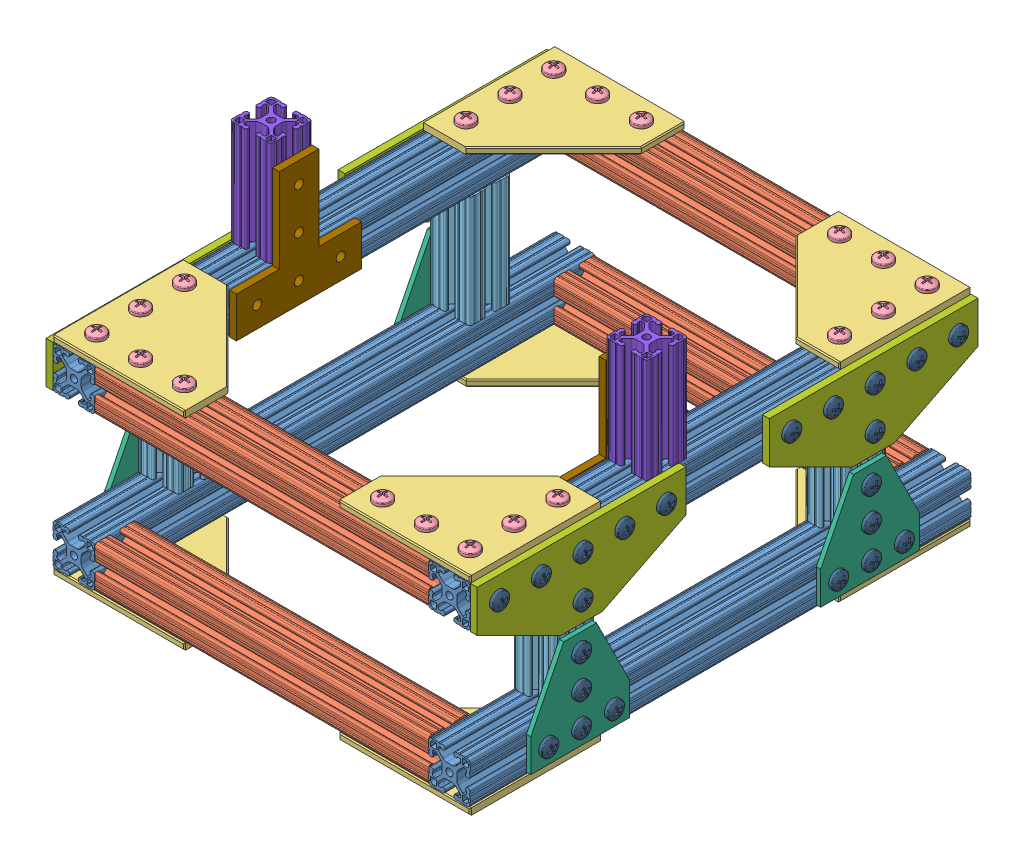
SolidWorks assembly 8020 stand, configuration Default. Lengths in mm.
Overall size (404.67 284.81 457.3).
118 component instances, 10 part files, 45 mates.
Components (placement in the parent):
- 8020 base-1: 8020 base [Default] at (-28.7494 167.9258 15.3611) x (-1 0 0) z (0 0 1) size (381.01 49.83 457.3)
  - 8020 14 inch-1: 8020 14 inch [Default] at (-104.9558 66.744 10.0389) size (38.14 38.25 457.2)
  - 8020 14 inch-2: 8020 14 inch [Default] at (237.9237 66.744 10.0389) size (38.14 38.25 457.2)
  - 8020 8 inch-1: 8020 8 inch [Default] at (34.7301 66.6403 98.9247) x (0 0 -1) z (1 0 0) size (38.14 38.25 304.8)
  - 8020 8 inch-2: 8020 8 inch [Default] at (288.7301 66.744 327.553) x (0 0 1) z (-1 0 0) size (38.14 38.25 304.8)
  - 8020 5 hole plate-1: 8020 5 hole plate [Default] at (29.7356 167.9258 361.7911) x (1 0 0) z (0 -1 0) size (120 120 6)
  - 8020 5 hole plate-2: 8020 5 hole plate [Default] at (293.7245 161.9258 361.7911) x (-1 0 0) z (0 1 0) size (120 120 6)
  - 8020 5 hole plate-3: 8020 5 hole plate [Default] at (293.7245 168.1331 64.6867) x (-1 0 0) z (0 -1 0) size (120 120 6)
  - 8020 5 hole plate-4: 8020 5 hole plate [Default] at (51.2984 167.9258 43.1239) x (0 0 1) z (0 -1 0) size (120 120 6)
  - CR-PHMS 0.3125-18x0.5x0.5-N-1: CR-PHMS 0.3125-18x0.5x0.5-N [CR-PHMS 0.3125-18x0.5x0.5-N] at (332.2095 173.6703 84.6389) x (0 -1 0) z (0 0 1) size (18.18 15.62 15.62)
  - CR-PHMS 0.3125-18x0.5x0.5-N-2: CR-PHMS 0.3125-18x0.5x0.5-N [CR-PHMS 0.3125-18x0.5x0.5-N] at (332.2095 173.6703 44.6389) x (0 -1 0) z (0 0 1) size (18.18 15.62 15.62)
  - CR-PHMS 0.3125-18x0.5x0.5-N-3: CR-PHMS 0.3125-18x0.5x0.5-N [CR-PHMS 0.3125-18x0.5x0.5-N] at (332.2095 173.6703 4.6389) x (0 -1 0) z (0 0 1) size (18.18 15.62 15.62)
  - CR-PHMS 0.3125-18x0.5x0.5-N-4: CR-PHMS 0.3125-18x0.5x0.5-N [CR-PHMS 0.3125-18x0.5x0.5-N] at (292.2095 173.6703 4.6389) x (0 -1 0) z (0 0 1) size (18.18 15.62 15.62)
  - CR-PHMS 0.3125-18x0.5x0.5-N-5: CR-PHMS 0.3125-18x0.5x0.5-N [CR-PHMS 0.3125-18x0.5x0.5-N] at (252.2095 173.6703 4.6389) x (0 -1 0) z (0 0 1) size (18.18 15.62 15.62)
  - CR-PHMS 0.3125-18x0.5x0.5-N-6: CR-PHMS 0.3125-18x0.5x0.5-N [CR-PHMS 0.3125-18x0.5x0.5-N] at (-8.7494 173.463 84.6389) x (0 -1 0) z (0 0 1) size (18.18 15.62 15.62)
  - CR-PHMS 0.3125-18x0.5x0.5-N-7: CR-PHMS 0.3125-18x0.5x0.5-N [CR-PHMS 0.3125-18x0.5x0.5-N] at (-8.7494 173.463 44.6389) x (0 -1 0) z (0 0 1) size (18.18 15.62 15.62)
  - CR-PHMS 0.3125-18x0.5x0.5-N-8: CR-PHMS 0.3125-18x0.5x0.5-N [CR-PHMS 0.3125-18x0.5x0.5-N] at (-8.7494 173.463 4.6389) x (0 -1 0) z (0 0 1) size (18.18 15.62 15.62)
  - CR-PHMS 0.3125-18x0.5x0.5-N-9: CR-PHMS 0.3125-18x0.5x0.5-N [CR-PHMS 0.3125-18x0.5x0.5-N] at (31.2506 173.463 4.6389) x (0 -1 0) z (0 0 1) size (18.18 15.62 15.62)
  - CR-PHMS 0.3125-18x0.5x0.5-N-10: CR-PHMS 0.3125-18x0.5x0.5-N [CR-PHMS 0.3125-18x0.5x0.5-N] at (71.2506 173.463 4.6389) x (0 -1 0) z (0 0 1) size (18.18 15.62 15.62)
  - CR-PHMS 0.3125-18x0.5x0.5-N-11: CR-PHMS 0.3125-18x0.5x0.5-N [CR-PHMS 0.3125-18x0.5x0.5-N] at (-8.7494 173.463 341.8389) x (0 -1 0) z (0 0 1) size (18.18 15.62 15.62)
  - CR-PHMS 0.3125-18x0.5x0.5-N-12: CR-PHMS 0.3125-18x0.5x0.5-N [CR-PHMS 0.3125-18x0.5x0.5-N] at (-8.7494 173.463 381.8389) x (0 -1 0) z (0 0 1) size (18.18 15.62 15.62)
  - CR-PHMS 0.3125-18x0.5x0.5-N-13: CR-PHMS 0.3125-18x0.5x0.5-N [CR-PHMS 0.3125-18x0.5x0.5-N] at (-8.7494 173.463 421.8389) x (0 -1 0) z (0 0 1) size (18.18 15.62 15.62)
  - CR-PHMS 0.3125-18x0.5x0.5-N-14: CR-PHMS 0.3125-18x0.5x0.5-N [CR-PHMS 0.3125-18x0.5x0.5-N] at (31.2506 173.463 421.8389) x (0 -1 0) z (0 0 1) size (18.18 15.62 15.62)
  - CR-PHMS 0.3125-18x0.5x0.5-N-15: CR-PHMS 0.3125-18x0.5x0.5-N [CR-PHMS 0.3125-18x0.5x0.5-N] at (71.2506 173.463 421.8389) x (0 -1 0) z (0 0 1) size (18.18 15.62 15.62)
  - CR-PHMS 0.3125-18x0.5x0.5-N-16: CR-PHMS 0.3125-18x0.5x0.5-N [CR-PHMS 0.3125-18x0.5x0.5-N] at (332.2095 173.463 421.8389) x (0 -1 0) z (0 0 1) size (18.18 15.62 15.62)
  - CR-PHMS 0.3125-18x0.5x0.5-N-17: CR-PHMS 0.3125-18x0.5x0.5-N [CR-PHMS 0.3125-18x0.5x0.5-N] at (292.2095 173.463 421.8389) x (0 -1 0) z (0 0 1) size (18.18 15.62 15.62)
  - CR-PHMS 0.3125-18x0.5x0.5-N-18: CR-PHMS 0.3125-18x0.5x0.5-N [CR-PHMS 0.3125-18x0.5x0.5-N] at (252.2095 173.463 421.8389) x (0 -1 0) z (0 0 1) size (18.18 15.62 15.62)
  - CR-PHMS 0.3125-18x0.5x0.5-N-19: CR-PHMS 0.3125-18x0.5x0.5-N [CR-PHMS 0.3125-18x0.5x0.5-N] at (332.2095 173.463 381.8389) x (0 -1 0) z (0 0 1) size (18.18 15.62 15.62)
  - CR-PHMS 0.3125-18x0.5x0.5-N-20: CR-PHMS 0.3125-18x0.5x0.5-N [CR-PHMS 0.3125-18x0.5x0.5-N] at (332.2095 173.463 341.8389) x (0 -1 0) z (0 0 1) size (18.18 15.62 15.62)
- 8020 base-2: 8020 base [Default] at (-352.2326 21.7379 15.3611) size (381.01 49.83 457.3)
  - 8020 14 inch-1: 8020 14 inch [Default] at (-104.9558 66.744 10.0389) size (38.14 38.25 457.2)
  - 8020 14 inch-2: 8020 14 inch [Default] at (237.9237 66.744 10.0389) size (38.14 38.25 457.2)
  - 8020 8 inch-1: 8020 8 inch [Default] at (34.7301 66.6403 98.9247) x (0 0 -1) z (1 0 0) size (38.14 38.25 304.8)
  - 8020 8 inch-2: 8020 8 inch [Default] at (288.7301 66.744 327.553) x (0 0 1) z (-1 0 0) size (38.14 38.25 304.8)
  - 8020 5 hole plate-1: 8020 5 hole plate [Default] at (29.7356 167.9258 361.7911) x (1 0 0) z (0 -1 0) size (120 120 6)
  - 8020 5 hole plate-2: 8020 5 hole plate [Default] at (293.7245 161.9258 361.7911) x (-1 0 0) z (0 1 0) size (120 120 6)
  - 8020 5 hole plate-3: 8020 5 hole plate [Default] at (293.7245 168.1331 64.6867) x (-1 0 0) z (0 -1 0) size (120 120 6)
  - 8020 5 hole plate-4: 8020 5 hole plate [Default] at (51.2984 167.9258 43.1239) x (0 0 1) z (0 -1 0) size (120 120 6)
  - CR-PHMS 0.3125-18x0.5x0.5-N-1: CR-PHMS 0.3125-18x0.5x0.5-N [CR-PHMS 0.3125-18x0.5x0.5-N] at (332.2095 173.6703 84.6389) x (0 -1 0) z (0 0 1) size (18.18 15.62 15.62)
  - CR-PHMS 0.3125-18x0.5x0.5-N-2: CR-PHMS 0.3125-18x0.5x0.5-N [CR-PHMS 0.3125-18x0.5x0.5-N] at (332.2095 173.6703 44.6389) x (0 -1 0) z (0 0 1) size (18.18 15.62 15.62)
  - CR-PHMS 0.3125-18x0.5x0.5-N-3: CR-PHMS 0.3125-18x0.5x0.5-N [CR-PHMS 0.3125-18x0.5x0.5-N] at (332.2095 173.6703 4.6389) x (0 -1 0) z (0 0 1) size (18.18 15.62 15.62)
  - CR-PHMS 0.3125-18x0.5x0.5-N-4: CR-PHMS 0.3125-18x0.5x0.5-N [CR-PHMS 0.3125-18x0.5x0.5-N] at (292.2095 173.6703 4.6389) x (0 -1 0) z (0 0 1) size (18.18 15.62 15.62)
  - CR-PHMS 0.3125-18x0.5x0.5-N-5: CR-PHMS 0.3125-18x0.5x0.5-N [CR-PHMS 0.3125-18x0.5x0.5-N] at (252.2095 173.6703 4.6389) x (0 -1 0) z (0 0 1) size (18.18 15.62 15.62)
  - CR-PHMS 0.3125-18x0.5x0.5-N-6: CR-PHMS 0.3125-18x0.5x0.5-N [CR-PHMS 0.3125-18x0.5x0.5-N] at (-8.7494 173.463 84.6389) x (0 -1 0) z (0 0 1) size (18.18 15.62 15.62)
  - CR-PHMS 0.3125-18x0.5x0.5-N-7: CR-PHMS 0.3125-18x0.5x0.5-N [CR-PHMS 0.3125-18x0.5x0.5-N] at (-8.7494 173.463 44.6389) x (0 -1 0) z (0 0 1) size (18.18 15.62 15.62)
  - CR-PHMS 0.3125-18x0.5x0.5-N-8: CR-PHMS 0.3125-18x0.5x0.5-N [CR-PHMS 0.3125-18x0.5x0.5-N] at (-8.7494 173.463 4.6389) x (0 -1 0) z (0 0 1) size (18.18 15.62 15.62)
  - CR-PHMS 0.3125-18x0.5x0.5-N-9: CR-PHMS 0.3125-18x0.5x0.5-N [CR-PHMS 0.3125-18x0.5x0.5-N] at (31.2506 173.463 4.6389) x (0 -1 0) z (0 0 1) size (18.18 15.62 15.62)
  - CR-PHMS 0.3125-18x0.5x0.5-N-10: CR-PHMS 0.3125-18x0.5x0.5-N [CR-PHMS 0.3125-18x0.5x0.5-N] at (71.2506 173.463 4.6389) x (0 -1 0) z (0 0 1) size (18.18 15.62 15.62)
  - CR-PHMS 0.3125-18x0.5x0.5-N-11: CR-PHMS 0.3125-18x0.5x0.5-N [CR-PHMS 0.3125-18x0.5x0.5-N] at (-8.7494 173.463 341.8389) x (0 -1 0) z (0 0 1) size (18.18 15.62 15.62)
  - CR-PHMS 0.3125-18x0.5x0.5-N-12: CR-PHMS 0.3125-18x0.5x0.5-N [CR-PHMS 0.3125-18x0.5x0.5-N] at (-8.7494 173.463 381.8389) x (0 -1 0) z (0 0 1) size (18.18 15.62 15.62)
  - CR-PHMS 0.3125-18x0.5x0.5-N-13: CR-PHMS 0.3125-18x0.5x0.5-N [CR-PHMS 0.3125-18x0.5x0.5-N] at (-8.7494 173.463 421.8389) x (0 -1 0) z (0 0 1) size (18.18 15.62 15.62)
  - CR-PHMS 0.3125-18x0.5x0.5-N-14: CR-PHMS 0.3125-18x0.5x0.5-N [CR-PHMS 0.3125-18x0.5x0.5-N] at (31.2506 173.463 421.8389) x (0 -1 0) z (0 0 1) size (18.18 15.62 15.62)
  - CR-PHMS 0.3125-18x0.5x0.5-N-15: CR-PHMS 0.3125-18x0.5x0.5-N [CR-PHMS 0.3125-18x0.5x0.5-N] at (71.2506 173.463 421.8389) x (0 -1 0) z (0 0 1) size (18.18 15.62 15.62)
  - CR-PHMS 0.3125-18x0.5x0.5-N-16: CR-PHMS 0.3125-18x0.5x0.5-N [CR-PHMS 0.3125-18x0.5x0.5-N] at (332.2095 173.463 421.8389) x (0 -1 0) z (0 0 1) size (18.18 15.62 15.62)
  - CR-PHMS 0.3125-18x0.5x0.5-N-17: CR-PHMS 0.3125-18x0.5x0.5-N [CR-PHMS 0.3125-18x0.5x0.5-N] at (292.2095 173.463 421.8389) x (0 -1 0) z (0 0 1) size (18.18 15.62 15.62)
  - CR-PHMS 0.3125-18x0.5x0.5-N-18: CR-PHMS 0.3125-18x0.5x0.5-N [CR-PHMS 0.3125-18x0.5x0.5-N] at (252.2095 173.463 421.8389) x (0 -1 0) z (0 0 1) size (18.18 15.62 15.62)
  - CR-PHMS 0.3125-18x0.5x0.5-N-19: CR-PHMS 0.3125-18x0.5x0.5-N [CR-PHMS 0.3125-18x0.5x0.5-N] at (332.2095 173.463 381.8389) x (0 -1 0) z (0 0 1) size (18.18 15.62 15.62)
  - CR-PHMS 0.3125-18x0.5x0.5-N-20: CR-PHMS 0.3125-18x0.5x0.5-N [CR-PHMS 0.3125-18x0.5x0.5-N] at (332.2095 173.463 341.8389) x (0 -1 0) z (0 0 1) size (18.18 15.62 15.62)
- 8020 4 inch-4: 8020 4 inch [Default] at (-114.2794 120.2318 285.5457) x (1 0 0) z (0 -1 0) size (38.14 38.25 101.6)
- 8020 T plate-1: 8020 T plate [Default] at (4.0064 1.7166 361.919) x (0 0 1) z (-1 0 0) size (90 90 4)
- 8020 T plate 2-1: 8020 T plate 2 [Default] at (6.3564 183.9362 266.7) x (0 0 -1) z (0 -1 0) size (190.5 6.35 76.2)
- 8020 4 inch-5: 8020 4 inch [Default] at (-114.2794 69.4318 171.6543) x (1 0 0) z (0 1 0) size (38.14 38.25 101.6)
- 8020 T plate 2-2: 8020 T plate 2 [Default] at (6.3564 183.9362 0) x (0 0 -1) z (0 -1 0) size (190.5 6.35 76.2)
- 8020 T plate-5: 8020 T plate [Default] at (0.0064 1.7166 95.281) x (0 0 -1) z (1 0 0) size (90 90 4)
- 8020 T plate 2-3: 8020 T plate 2 [Default] at (-387.3564 183.9362 457.2) x (0 0 1) z (0 -1 0) size (190.5 6.35 76.2)
- 8020 T plate 2-4: 8020 T plate 2 [Default] at (-387.3564 183.9362 190.5) x (0 0 1) z (0 -1 0) size (190.5 6.35 76.2)
- 8020 4 inch-6: 8020 4 inch [Default] at (-266.7206 120.2318 171.6543) x (-1 0 0) z (0 -1 0) size (38.14 38.25 101.6)
- 8020 T plate-6: 8020 T plate [Default] at (-385.0064 1.7166 95.281) x (0 0 -1) z (1 0 0) size (90 90 4)
- 8020 T plate-7: 8020 T plate [Default] at (-381.0064 1.7166 361.919) x (0 0 1) z (-1 0 0) size (90 90 4)
- 8020 4 inch-7: 8020 4 inch [Default] at (-266.7206 69.4318 285.5457) x (-1 0 0) z (0 1 0) size (38.14 38.25 101.6)
- 8020 5 inch-1: 8020 5 inch [Default] at (-114.309 209.271 353.3149) x (1 0 0) z (0 1 0) size (38.14 38.25 95.25)
- 8020 thin t-1: 8020 thin t [Default] at (-38.1026 145.7334 219.8633) x (0 0 1) z (0 1 0) size (114.3 6.35 114.3)
- 8020 5 inch-2: 8020 5 inch [Default] at (-266.691 253.721 353.3149) x (-1 0 0) z (0 -1 0) size (38.14 38.25 95.25)
- 8020 thin t-2: 8020 thin t [Default] at (-342.8974 145.7334 334.1633) x (0 0 -1) z (0 1 0) size (114.3 6.35 114.3)
- CR-PHMS 0.3125-24x0.5x0.5-N-2: CR-PHMS 0.3125-24x0.5x0.5-N [CR-PHMS 0.3125-24x0.5x0.5-N] at (11.8936 164.8862 438.15) x (-1 0 0) z (0 0.924225 0.381849) size (18.18 15.62 15.62)
- CR-PHMS 0.3125-24x0.5x0.5-N-3: CR-PHMS 0.3125-24x0.5x0.5-N [CR-PHMS 0.3125-24x0.5x0.5-N] at (11.8936 164.8862 400.05) x (-1 0 0) z (0 0.924225 0.381849) size (18.18 15.62 15.62)
- CR-PHMS 0.3125-24x0.5x0.5-N-4: CR-PHMS 0.3125-24x0.5x0.5-N [CR-PHMS 0.3125-24x0.5x0.5-N] at (11.8936 164.8862 361.95) x (-1 0 0) z (0 0.924225 0.381849) size (18.18 15.62 15.62)
- CR-PHMS 0.3125-24x0.5x0.5-N-5: CR-PHMS 0.3125-24x0.5x0.5-N [CR-PHMS 0.3125-24x0.5x0.5-N] at (11.8936 164.8862 323.85) x (-1 0 0) z (0 0.924225 0.381849) size (18.18 15.62 15.62)
- CR-PHMS 0.3125-24x0.5x0.5-N-6: CR-PHMS 0.3125-24x0.5x0.5-N [CR-PHMS 0.3125-24x0.5x0.5-N] at (11.8936 164.8862 285.75) x (-1 0 0) z (0 0.924225 0.381849) size (18.18 15.62 15.62)
- CR-PHMS 0.3125-24x0.5x0.5-N-7: CR-PHMS 0.3125-24x0.5x0.5-N [CR-PHMS 0.3125-24x0.5x0.5-N] at (11.8936 126.7862 361.95) x (-1 0 0) z (0 0.924225 0.381849) size (18.18 15.62 15.62)
- CR-PHMS 0.3125-24x0.5x0.5-N-8: CR-PHMS 0.3125-24x0.5x0.5-N [CR-PHMS 0.3125-24x0.5x0.5-N] at (9.5436 84.0323 360.9344) x (-1 0 0) z (0 0.924225 0.381849) size (18.18 15.62 15.62)
- CR-PHMS 0.3125-24x0.5x0.5-N-9: CR-PHMS 0.3125-24x0.5x0.5-N [CR-PHMS 0.3125-24x0.5x0.5-N] at (9.5436 54.0323 360.9344) x (-1 0 0) z (0 0.924225 0.381849) size (18.18 15.62 15.62)
- CR-PHMS 0.3125-24x0.5x0.5-N-10: CR-PHMS 0.3125-24x0.5x0.5-N [CR-PHMS 0.3125-24x0.5x0.5-N] at (9.5436 24.0323 330.9344) x (-1 0 0) z (0 0.924225 0.381849) size (18.18 15.62 15.62)
- CR-PHMS 0.3125-24x0.5x0.5-N-11: CR-PHMS 0.3125-24x0.5x0.5-N [CR-PHMS 0.3125-24x0.5x0.5-N] at (9.5436 24.0323 360.9344) x (-1 0 0) z (0 0.924225 0.381849) size (18.18 15.62 15.62)
- CR-PHMS 0.3125-24x0.5x0.5-N-12: CR-PHMS 0.3125-24x0.5x0.5-N [CR-PHMS 0.3125-24x0.5x0.5-N] at (9.5436 24.0323 390.9344) x (-1 0 0) z (0 0.924225 0.381849) size (18.18 15.62 15.62)
- CR-PHMS 0.3125-24x0.5x0.5-N-13: CR-PHMS 0.3125-24x0.5x0.5-N [CR-PHMS 0.3125-24x0.5x0.5-N] at (11.8936 164.8862 19.05) x (-1 0 0) z (0 -0.924225 0.381849) size (18.18 15.62 15.62)
- CR-PHMS 0.3125-24x0.5x0.5-N-14: CR-PHMS 0.3125-24x0.5x0.5-N [CR-PHMS 0.3125-24x0.5x0.5-N] at (11.8936 164.8862 95.25) x (-1 0 0) z (0 -0.924225 0.381849) size (18.18 15.62 15.62)
- CR-PHMS 0.3125-24x0.5x0.5-N-15: CR-PHMS 0.3125-24x0.5x0.5-N [CR-PHMS 0.3125-24x0.5x0.5-N] at (11.8936 164.8862 133.35) x (-1 0 0) z (0 -0.924225 0.381849) size (18.18 15.62 15.62)
- CR-PHMS 0.3125-24x0.5x0.5-N-16: CR-PHMS 0.3125-24x0.5x0.5-N [CR-PHMS 0.3125-24x0.5x0.5-N] at (11.8936 164.8862 171.45) x (-1 0 0) z (0 -0.924225 0.381849) size (18.18 15.62 15.62)
- CR-PHMS 0.3125-24x0.5x0.5-N-17: CR-PHMS 0.3125-24x0.5x0.5-N [CR-PHMS 0.3125-24x0.5x0.5-N] at (11.8936 126.7862 95.25) x (-1 0 0) z (0 -0.924225 0.381849) size (18.18 15.62 15.62)
- CR-PHMS 0.3125-24x0.5x0.5-N-18: CR-PHMS 0.3125-24x0.5x0.5-N [CR-PHMS 0.3125-24x0.5x0.5-N] at (11.8936 164.8862 57.15) x (-1 0 0) z (0 -0.924225 0.381849) size (18.18 15.62 15.62)
- CR-PHMS 0.3125-24x0.5x0.5-N-19: CR-PHMS 0.3125-24x0.5x0.5-N [CR-PHMS 0.3125-24x0.5x0.5-N] at (9.5436 54.0323 96.2656) x (-1 0 0) z (0 -0.924225 0.381849) size (18.18 15.62 15.62)
- CR-PHMS 0.3125-24x0.5x0.5-N-20: CR-PHMS 0.3125-24x0.5x0.5-N [CR-PHMS 0.3125-24x0.5x0.5-N] at (9.5436 24.0323 96.2656) x (-1 0 0) z (0 -0.924225 0.381849) size (18.18 15.62 15.62)
- CR-PHMS 0.3125-24x0.5x0.5-N-21: CR-PHMS 0.3125-24x0.5x0.5-N [CR-PHMS 0.3125-24x0.5x0.5-N] at (9.5436 24.0323 66.2656) x (-1 0 0) z (0 -0.924225 0.381849) size (18.18 15.62 15.62)
- CR-PHMS 0.3125-24x0.5x0.5-N-22: CR-PHMS 0.3125-24x0.5x0.5-N [CR-PHMS 0.3125-24x0.5x0.5-N] at (9.5436 24.0323 126.2656) x (-1 0 0) z (0 -0.924225 0.381849) size (18.18 15.62 15.62)
- CR-PHMS 0.3125-24x0.5x0.5-N-23: CR-PHMS 0.3125-24x0.5x0.5-N [CR-PHMS 0.3125-24x0.5x0.5-N] at (9.5436 84.0323 96.2656) x (-1 0 0) z (0 -0.924225 0.381849) size (18.18 15.62 15.62)
- CR-PHMS 0.3125-24x0.5x0.5-N-24: CR-PHMS 0.3125-24x0.5x0.5-N [CR-PHMS 0.3125-24x0.5x0.5-N] at (-392.8936 164.8862 438.15) x (1 0 0) z (0 -0.924225 -0.381849) size (18.18 15.62 15.62)
- CR-PHMS 0.3125-24x0.5x0.5-N-25: CR-PHMS 0.3125-24x0.5x0.5-N [CR-PHMS 0.3125-24x0.5x0.5-N] at (-392.8936 164.8862 361.95) x (1 0 0) z (0 -0.924225 -0.381849) size (18.18 15.62 15.62)
- CR-PHMS 0.3125-24x0.5x0.5-N-26: CR-PHMS 0.3125-24x0.5x0.5-N [CR-PHMS 0.3125-24x0.5x0.5-N] at (-392.8936 164.8862 323.85) x (1 0 0) z (0 -0.924225 -0.381849) size (18.18 15.62 15.62)
- CR-PHMS 0.3125-24x0.5x0.5-N-27: CR-PHMS 0.3125-24x0.5x0.5-N [CR-PHMS 0.3125-24x0.5x0.5-N] at (-392.8936 164.8862 285.75) x (1 0 0) z (0 -0.924225 -0.381849) size (18.18 15.62 15.62)
- CR-PHMS 0.3125-24x0.5x0.5-N-28: CR-PHMS 0.3125-24x0.5x0.5-N [CR-PHMS 0.3125-24x0.5x0.5-N] at (-392.8936 126.7862 361.95) x (1 0 0) z (0 -0.924225 -0.381849) size (18.18 15.62 15.62)
- CR-PHMS 0.3125-24x0.5x0.5-N-29: CR-PHMS 0.3125-24x0.5x0.5-N [CR-PHMS 0.3125-24x0.5x0.5-N] at (-392.8936 164.8862 400.05) x (1 0 0) z (0 -0.924225 -0.381849) size (18.18 15.62 15.62)
- CR-PHMS 0.3125-24x0.5x0.5-N-30: CR-PHMS 0.3125-24x0.5x0.5-N [CR-PHMS 0.3125-24x0.5x0.5-N] at (-390.5436 54.0323 360.9344) x (1 0 0) z (0 -0.924225 -0.381849) size (18.18 15.62 15.62)
- CR-PHMS 0.3125-24x0.5x0.5-N-31: CR-PHMS 0.3125-24x0.5x0.5-N [CR-PHMS 0.3125-24x0.5x0.5-N] at (-390.5436 24.0323 360.9344) x (1 0 0) z (0 -0.924225 -0.381849) size (18.18 15.62 15.62)
- CR-PHMS 0.3125-24x0.5x0.5-N-32: CR-PHMS 0.3125-24x0.5x0.5-N [CR-PHMS 0.3125-24x0.5x0.5-N] at (-390.5436 24.0323 390.9344) x (1 0 0) z (0 -0.924225 -0.381849) size (18.18 15.62 15.62)
- CR-PHMS 0.3125-24x0.5x0.5-N-33: CR-PHMS 0.3125-24x0.5x0.5-N [CR-PHMS 0.3125-24x0.5x0.5-N] at (-390.5436 24.0323 330.9344) x (1 0 0) z (0 -0.924225 -0.381849) size (18.18 15.62 15.62)
- CR-PHMS 0.3125-24x0.5x0.5-N-34: CR-PHMS 0.3125-24x0.5x0.5-N [CR-PHMS 0.3125-24x0.5x0.5-N] at (-390.5436 84.0323 360.9344) x (1 0 0) z (0 -0.924225 -0.381849) size (18.18 15.62 15.62)
- CR-PHMS 0.3125-24x0.5x0.5-N-35: CR-PHMS 0.3125-24x0.5x0.5-N [CR-PHMS 0.3125-24x0.5x0.5-N] at (-392.8936 164.8862 19.05) x (1 0 0) z (0 0.924225 -0.381849) size (18.18 15.62 15.62)
- CR-PHMS 0.3125-24x0.5x0.5-N-36: CR-PHMS 0.3125-24x0.5x0.5-N [CR-PHMS 0.3125-24x0.5x0.5-N] at (-392.8936 164.8862 95.25) x (1 0 0) z (0 0.924225 -0.381849) size (18.18 15.62 15.62)
- CR-PHMS 0.3125-24x0.5x0.5-N-37: CR-PHMS 0.3125-24x0.5x0.5-N [CR-PHMS 0.3125-24x0.5x0.5-N] at (-392.8936 164.8862 133.35) x (1 0 0) z (0 0.924225 -0.381849) size (18.18 15.62 15.62)
- CR-PHMS 0.3125-24x0.5x0.5-N-38: CR-PHMS 0.3125-24x0.5x0.5-N [CR-PHMS 0.3125-24x0.5x0.5-N] at (-392.8936 164.8862 171.45) x (1 0 0) z (0 0.924225 -0.381849) size (18.18 15.62 15.62)
- CR-PHMS 0.3125-24x0.5x0.5-N-39: CR-PHMS 0.3125-24x0.5x0.5-N [CR-PHMS 0.3125-24x0.5x0.5-N] at (-392.8936 126.7862 95.25) x (1 0 0) z (0 0.924225 -0.381849) size (18.18 15.62 15.62)
- CR-PHMS 0.3125-24x0.5x0.5-N-40: CR-PHMS 0.3125-24x0.5x0.5-N [CR-PHMS 0.3125-24x0.5x0.5-N] at (-392.8936 164.8862 57.15) x (1 0 0) z (0 0.924225 -0.381849) size (18.18 15.62 15.62)
- CR-PHMS 0.3125-24x0.5x0.5-N-41: CR-PHMS 0.3125-24x0.5x0.5-N [CR-PHMS 0.3125-24x0.5x0.5-N] at (-390.5436 54.0323 96.2656) x (1 0 0) z (0 0.924225 -0.381849) size (18.18 15.62 15.62)
- CR-PHMS 0.3125-24x0.5x0.5-N-42: CR-PHMS 0.3125-24x0.5x0.5-N [CR-PHMS 0.3125-24x0.5x0.5-N] at (-390.5436 24.0323 96.2656) x (1 0 0) z (0 0.924225 -0.381849) size (18.18 15.62 15.62)
- CR-PHMS 0.3125-24x0.5x0.5-N-43: CR-PHMS 0.3125-24x0.5x0.5-N [CR-PHMS 0.3125-24x0.5x0.5-N] at (-390.5436 24.0323 66.2656) x (1 0 0) z (0 0.924225 -0.381849) size (18.18 15.62 15.62)
- CR-PHMS 0.3125-24x0.5x0.5-N-44: CR-PHMS 0.3125-24x0.5x0.5-N [CR-PHMS 0.3125-24x0.5x0.5-N] at (-390.5436 24.0323 126.2656) x (1 0 0) z (0 0.924225 -0.381849) size (18.18 15.62 15.62)
- CR-PHMS 0.3125-24x0.5x0.5-N-45: CR-PHMS 0.3125-24x0.5x0.5-N [CR-PHMS 0.3125-24x0.5x0.5-N] at (-390.5436 84.0323 96.2656) x (1 0 0) z (0 0.924225 -0.381849) size (18.18 15.62 15.62)
Mates (geometry in assembly coordinates):
- Coincident1: coincident anti-aligned: plane of 8020 base-1/8020 5 hole plate-1 through (0 0 338.2) normal (0 -1 0); plane of assembly through (0 0 0) normal (0 1 0)
- Coincident2: coincident aligned: plane of 8020 base-1/8020 5 hole plate-1 through (0 0 338.2) normal (1 0 0); plane of assembly through (0 0 0) normal (1 0 0)
- Coincident5: coincident anti-aligned: plane of 8020 base-1/8020 14 inch-1 through (-6.3435 44.0318 457.2) normal (0 1 0); plane of 8020 4 inch-4 through (-25.5 44.0318 376.9287) normal (0 -1 0)
- Coincident6: coincident aligned: plane of 8020 base-1/8020 14 inch-1 through (0.0064 39.3074 457.2) normal (1 0 0); plane of 8020 4 inch-4 through (0.0064 44.0318 376.2105) normal (1 0 0)
- Coincident10: coincident aligned: plane of 8020 base-2/8020 14 inch-2 through (0.0064 152.0846 457.2) normal (1 0 0); plane of 8020 4 inch-4 through (0.0064 44.0318 376.2105) normal (1 0 0)
- Coincident11: coincident anti-aligned: plane of 8020 base-1/8020 14 inch-1 through (0.0064 39.3074 457.2) normal (1 0 0); plane of 8020 T plate-1 through (0.0064 9.0323 405.9344) normal (-1 0 0)
- Tangent1: tangent anti-aligned: plane of 8020 base-1/8020 14 inch-1 through (-2.7372 20.8823 457.2) normal (0 1 0); cylinder of 8020 T plate-1 through (0.0064 24.0323 390.9344) axis (1 0 0) radius 3.15
- Tangent2: tangent anti-aligned: plane of 8020 base-1/8020 14 inch-1 through (-2.7372 20.8823 457.2) normal (0 1 0); cylinder of 8020 T plate-1 through (0.0064 24.0323 330.9344) axis (1 0 0) radius 3.15
- Tangent3: tangent anti-aligned: plane of 8020 4 inch-4 through (-2.7012 44.0318 357.7844) normal (0 0 1); cylinder of 8020 T plate-1 through (0.0064 84.0323 360.9344) axis (1 0 0) radius 3.15
- Coincident13: coincident anti-aligned: plane of 8020 base-2/8020 14 inch-2 through (0.0064 152.0846 457.2) normal (1 0 0); plane of 8020 T plate 2-1 through (0.0064 107.7362 266.7) normal (-1 0 0)
- Tangent6: tangent anti-aligned: plane of 8020 base-2/8020 14 inch-2 through (-2.7308 160.7206 457.2) normal (0 1 0); cylinder of 8020 T plate 2-1 through (6.3564 164.8862 285.75) axis (-1 0 0) radius 4.1656
- Coincident14: coincident anti-aligned: plane of 8020 base-2/8020 14 inch-2 through (-31.759 145.6318 457.2) normal (0 -1 0); plane of 8020 4 inch-4 through (-25.5 145.6318 376.9287) normal (0 1 0)
- Tangent7: tangent anti-aligned: plane of 8020 base-2/8020 14 inch-2 through (-2.7308 160.7206 457.2) normal (0 1 0); cylinder of 8020 T plate 2-1 through (0.0064 164.8862 438.15) axis (1 0 0) radius 4.1656
- Tangent8: tangent anti-aligned: plane of 8020 4 inch-4 through (-2.7012 44.0318 357.7844) normal (0 0 1); cylinder of 8020 T plate 2-1 through (0.0064 126.7862 361.95) axis (1 0 0) radius 4.1656
- Coincident15: coincident aligned: plane of 8020 base-2/8020 14 inch-2 through (-25.5296 179.8649 457.2) normal (0 0 1); plane of 8020 T plate 2-1 through (0.0064 145.8362 457.2) normal (0 0 1)
- Coincident16: coincident aligned: plane of 8020 base-1/8020 14 inch-1 through (-12.573 9.7988 457.2) normal (0 0 1); plane of 8020 base-2/8020 14 inch-2 through (-25.5296 179.8649 457.2) normal (0 0 1)
- Coincident18: coincident anti-aligned: plane of 8020 base-2/8020 14 inch-2 through (-25.5296 179.8649 0) normal (0 0 -1); plane of assembly through (0 0 0) normal (0 0 1)
- Coincident19: coincident anti-aligned: plane of 8020 base-2/8020 14 inch-2 through (-6.3731 183.871 457.2) normal (0 1 0); plane of 8020 5 inch-1 through (-25.5296 183.871 261.9318) normal (0 -1 0)
- Coincident20: coincident aligned: plane of 8020 base-2/8020 14 inch-2 through (-0.0231 179.1466 457.2) normal (1 0 0); plane of 8020 5 inch-1 through (-0.0231 279.121 262.6501) normal (1 0 0)
- Coincident22: coincident anti-aligned: plane of 8020 base-2/8020 14 inch-2 through (-38.1026 177.4174 457.2) normal (-1 0 0); plane of 8020 thin t-1 through (-38.1026 145.7334 219.8633) normal (1 0 0)
- Tangent9: tangent anti-aligned: plane of 8020 5 inch-1 through (-36.2867 279.121 281.1789) normal (0 0 -1); cylinder of 8020 thin t-1 through (-38.1026 240.9834 277.0133) axis (-1 0 0) radius 4.1656
- Tangent10: tangent anti-aligned: plane of 8020 base-2/8020 14 inch-2 through (-36.2867 160.6178 457.2) normal (0 1 0); cylinder of 8020 thin t-1 through (-38.1026 164.7834 315.1133) axis (-1 0 0) radius 4.1656
- Tangent11: tangent anti-aligned: plane of 8020 base-2/8020 14 inch-2 through (-36.2867 160.6178 457.2) normal (0 1 0); cylinder of 8020 thin t-1 through (-38.1026 164.7834 238.9133) axis (-1 0 0) radius 4.1656
- Concentric2: concentric aligned: cylinder of 8020 T plate 2-1 through (0.0064 164.8862 438.15) axis (1 0 0) radius 4.1656; cylinder of CR-PHMS 0.3125-24x0.5x0.5-N-2 through (37.2936 164.8862 438.15) axis (1 0 0) radius 7.8105
- Coincident25: coincident anti-aligned: plane of 8020 T plate 2-1 through (6.3564 107.7362 457.2) normal (1 0 0); plane of CR-PHMS 0.3125-24x0.5x0.5-N-2 through (6.3564 163.3707 441.818) normal (-1 0 0)
- Concentric3: concentric aligned: cylinder of 8020 T plate 2-1 through (0.0064 164.8862 400.05) axis (1 0 0) radius 4.1656; cylinder of CR-PHMS 0.3125-24x0.5x0.5-N-3 through (37.2936 164.8862 400.05) axis (1 0 0) radius 7.8105
- Coincident26: coincident anti-aligned: plane of 8020 T plate 2-1 through (6.3564 107.7362 457.2) normal (1 0 0); plane of CR-PHMS 0.3125-24x0.5x0.5-N-3 through (6.3564 163.3707 403.718) normal (-1 0 0)
- Concentric4: concentric aligned: cylinder of 8020 T plate 2-1 through (0.0064 164.8862 361.95) axis (1 0 0) radius 4.1656; cylinder of CR-PHMS 0.3125-24x0.5x0.5-N-4 through (37.2936 164.8862 361.95) axis (1 0 0) radius 7.8105
- Coincident27: coincident anti-aligned: plane of 8020 T plate 2-1 through (6.3564 107.7362 457.2) normal (1 0 0); plane of CR-PHMS 0.3125-24x0.5x0.5-N-4 through (6.3564 163.3707 365.618) normal (-1 0 0)
- Concentric5: concentric anti-aligned: cylinder of 8020 T plate 2-1 through (6.3564 164.8862 323.85) axis (-1 0 0) radius 4.1656; cylinder of CR-PHMS 0.3125-24x0.5x0.5-N-5 through (37.2936 164.8862 323.85) axis (1 0 0) radius 7.8105
- Coincident28: coincident anti-aligned: plane of 8020 T plate 2-1 through (6.3564 107.7362 457.2) normal (1 0 0); plane of CR-PHMS 0.3125-24x0.5x0.5-N-5 through (6.3564 163.3707 327.518) normal (-1 0 0)
- Concentric6: concentric anti-aligned: cylinder of 8020 T plate 2-1 through (6.3564 164.8862 285.75) axis (-1 0 0) radius 4.1656; cylinder of CR-PHMS 0.3125-24x0.5x0.5-N-6 through (37.2936 164.8862 285.75) axis (1 0 0) radius 7.8105
- Coincident29: coincident anti-aligned: plane of 8020 T plate 2-1 through (6.3564 107.7362 457.2) normal (1 0 0); plane of CR-PHMS 0.3125-24x0.5x0.5-N-6 through (6.3564 163.3707 289.418) normal (-1 0 0)
- Concentric7: concentric aligned: cylinder of 8020 T plate 2-1 through (0.0064 126.7862 361.95) axis (1 0 0) radius 4.1656; cylinder of CR-PHMS 0.3125-24x0.5x0.5-N-7 through (37.2936 126.7862 361.95) axis (1 0 0) radius 7.8105
- Coincident30: coincident anti-aligned: plane of 8020 T plate 2-1 through (6.3564 107.7362 457.2) normal (1 0 0); plane of CR-PHMS 0.3125-24x0.5x0.5-N-7 through (6.3564 125.2707 365.618) normal (-1 0 0)
- Concentric8: concentric aligned: cylinder of 8020 T plate-1 through (0.0064 84.0323 360.9344) axis (1 0 0) radius 3.15; cylinder of CR-PHMS 0.3125-24x0.5x0.5-N-8 through (34.9436 84.0323 360.9344) axis (1 0 0) radius 7.8105
- Coincident31: coincident anti-aligned: plane of 8020 T plate-1 through (4.0064 9.0323 405.9344) normal (1 0 0); plane of CR-PHMS 0.3125-24x0.5x0.5-N-8 through (4.0064 82.5168 364.6024) normal (-1 0 0)
- Concentric9: concentric aligned: cylinder of 8020 T plate-1 through (0.0064 54.0323 360.9344) axis (1 0 0) radius 3.15; cylinder of CR-PHMS 0.3125-24x0.5x0.5-N-9 through (34.9436 54.0323 360.9344) axis (1 0 0) radius 7.8105
- Coincident32: coincident anti-aligned: plane of 8020 T plate-1 through (4.0064 9.0323 405.9344) normal (1 0 0); plane of CR-PHMS 0.3125-24x0.5x0.5-N-9 through (4.0064 52.5168 364.6024) normal (-1 0 0)
- Concentric10: concentric aligned: cylinder of 8020 T plate-1 through (0.0064 24.0323 330.9344) axis (1 0 0) radius 3.15; cylinder of CR-PHMS 0.3125-24x0.5x0.5-N-10 through (34.9436 24.0323 330.9344) axis (1 0 0) radius 7.8105
- Coincident33: coincident anti-aligned: plane of 8020 T plate-1 through (4.0064 9.0323 405.9344) normal (1 0 0); plane of CR-PHMS 0.3125-24x0.5x0.5-N-10 through (4.0064 22.5168 334.6024) normal (-1 0 0)
- Concentric11: concentric aligned: cylinder of 8020 T plate-1 through (0.0064 24.0323 360.9344) axis (1 0 0) radius 3.15; cylinder of CR-PHMS 0.3125-24x0.5x0.5-N-11 through (34.9436 24.0323 360.9344) axis (1 0 0) radius 7.8105
- Coincident34: coincident anti-aligned: plane of 8020 T plate-1 through (4.0064 9.0323 405.9344) normal (1 0 0); plane of CR-PHMS 0.3125-24x0.5x0.5-N-11 through (4.0064 22.5168 364.6024) normal (-1 0 0)
- Concentric12: concentric aligned: cylinder of 8020 T plate-1 through (0.0064 24.0323 390.9344) axis (1 0 0) radius 3.15; cylinder of CR-PHMS 0.3125-24x0.5x0.5-N-12 through (34.9436 24.0323 390.9344) axis (1 0 0) radius 7.8105
- Coincident35: coincident anti-aligned: plane of 8020 T plate-1 through (4.0064 9.0323 405.9344) normal (1 0 0); plane of CR-PHMS 0.3125-24x0.5x0.5-N-12 through (4.0064 22.5168 394.6024) normal (-1 0 0)
